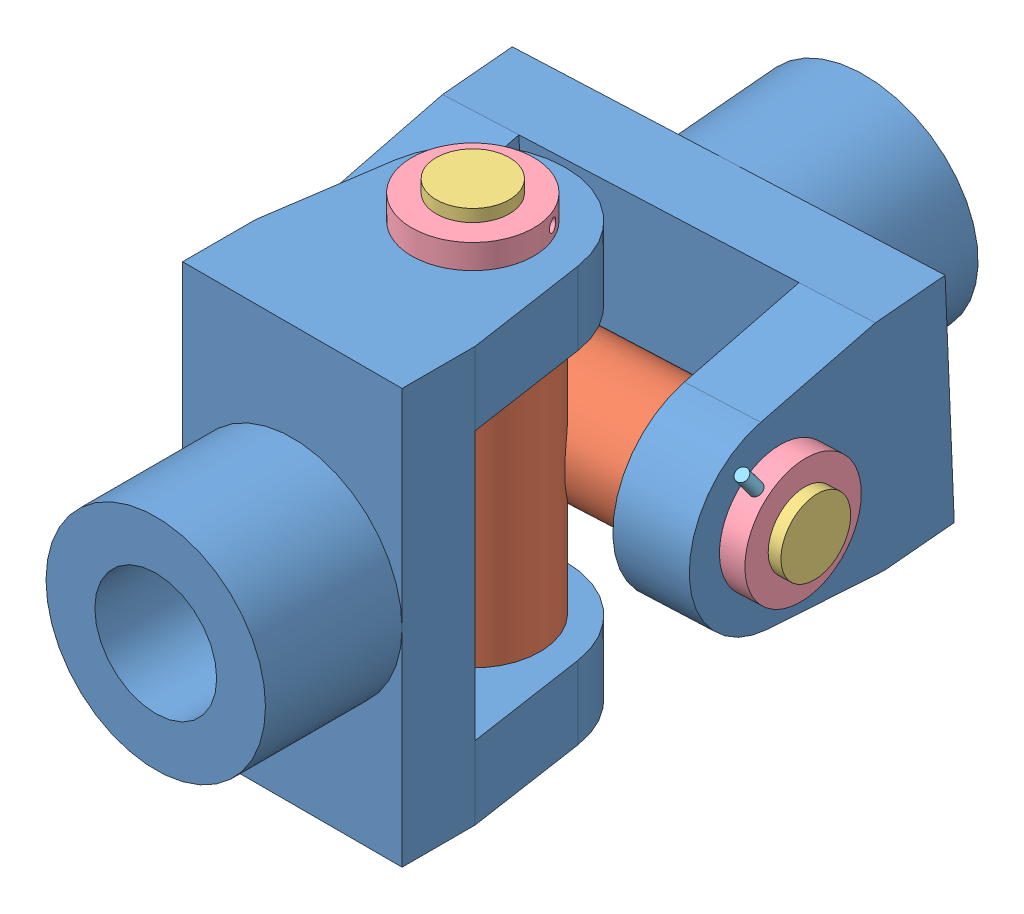
SolidWorks assembly minor project 1, configuration Default. Lengths in mm.
Overall size (197.94 195 303.49).
8 component instances, 5 part files, 14 mates.
Components (placement in the parent):
- fork-1: fork [Default] at (57.6071 83.4507 137.1528) size (90 170 168)
- center pin-5: center pin [Default] at (110.8453 84.1426 52.7215) x (0.044904 0 0.998991) z (-0.998991 0 0.044904) size (90.5 110 110)
- fork-5: fork [Default] at (53.9269 86.0638 11.2775) x (-0.001961 -0.999046 -0.043621) z (-0.044861 0.043665 -0.998039) size (90 170 168)
- pin-1: pin [Default] at (57.6071 -1.5493 93.1528) x (0.918137 0 -0.396263) z (0 -1 0) size (50 50 195)
- pin-2: pin [Default] at (-29.0135 84.1426 59.008) x (-0.02671 -0.803846 -0.594237) z (-0.998991 0 0.044904) size (50 50 195)
- coller-6: coller [Default] at (57.6071 178.4507 93.1528) x (0.396263 0 0.918137) z (0 -1 0) size (50 50 10)
- coller-7: coller [Default] at (140.8151 84.1426 51.3743) x (-0.036096 0.594837 -0.803036) z (0.998991 0 -0.044904) size (50 50 10)
- longer pin-1: longer pin [Default] at (145.1423 64.0464 36.2939) x (0.994729 0.037497 -0.095436) z (0.02671 0.803846 0.594237) size (6 6 60)
Mates (geometry in assembly coordinates):
- Concentric5: concentric aligned: cylinder of fork-1 through (57.6071 138.4507 93.1528) axis (0 1 0) radius 15; cylinder of center pin-5 through (57.6071 -13.2838 93.1528) axis (0 1 0) radius 15
- Concentric6: concentric anti-aligned: circle of fork-1; cylinder of center pin-5 through (57.6071 139.1426 93.1528) axis (0 -1 0) radius 27.5
- Concentric7: concentric anti-aligned: cylinder of center pin-5 through (153.2289 84.1426 50.8164) axis (-0.998991 0 0.044904) radius 15; cylinder of fork-5 through (110.8453 84.1426 52.7215) axis (0.998991 0 -0.044904) radius 15
- Coincident5: coincident anti-aligned: plane of center pin-5 through (110.8453 84.1426 52.7215) normal (0.998991 0 -0.044904); plane of fork-5 through (108.8714 86.0638 8.8078) normal (-0.998991 0 0.044904)
- Concentric8: concentric anti-aligned: cylinder of fork-1 through (57.6071 138.4507 93.1528) axis (0 1 0) radius 15; cylinder of pin-1 through (57.6071 183.4507 93.1528) axis (0 -1 0) radius 15
- Coincident9: coincident anti-aligned: plane of fork-1 through (12.6071 -1.5493 167.1528) normal (0 -1 0); plane of pin-1 through (57.6071 -1.5493 93.1528) normal (0 1 0)
- Concentric11: concentric aligned: line of fork-5; axis of pin-2 through (155.7999 84.1426 50.7008) axis (-0.998991 0 0.044904)
- Coincident10: coincident anti-aligned: plane of fork-5 through (-32.2449 132.3309 -12.884) normal (-0.998991 0 0.044904); plane of pin-2 through (-29.0135 84.1426 59.008) normal (0.998991 0 -0.044904)
- Concentric13: concentric anti-aligned: cylinder of pin-1 through (57.6071 183.4507 93.1528) axis (0 -1 0) radius 15; cylinder of coller-6 through (57.6071 168.4507 93.1528) axis (0 1 0) radius 15
- Coincident12: coincident anti-aligned: line of pin-1 through (43.8351 173.4507 99.0968) axis (0.918137 0 -0.396263); line of coller-6 through (43.8351 173.4507 99.0968) axis (-0.918137 0 0.396263)
- Concentric15: concentric aligned: cylinder of pin-2 through (155.7999 84.1426 50.7008) axis (-0.998991 0 0.044904) radius 15; cylinder of coller-7 through (150.805 84.1426 50.9253) axis (-0.998991 0 0.044904) radius 15
- Concentric16: concentric anti-aligned: cylinder of pin-2 through (148.2807 158.4984 106.1167) axis (-0.02671 -0.803846 -0.594237) radius 2.5; cylinder of coller-7 through (144.8084 53.9984 28.8659) axis (0.02671 0.803846 0.594237) radius 2.5
- Coincident13: coincident aligned: line of coller-7 through (145.1423 64.0464 36.2939) axis (0.02671 0.803846 0.594237); line of longer pin-1 through (145.1423 64.0464 36.2939) axis (0.02671 0.803846 0.594237)
- Tangent11: tangent aligned: cylinder of coller-7 through (150.805 84.1426 50.9253) axis (-0.998991 0 0.044904) radius 25; plane of longer pin-1 through (145.1423 64.0464 36.2939) normal (-0.02671 -0.803846 -0.594237)
